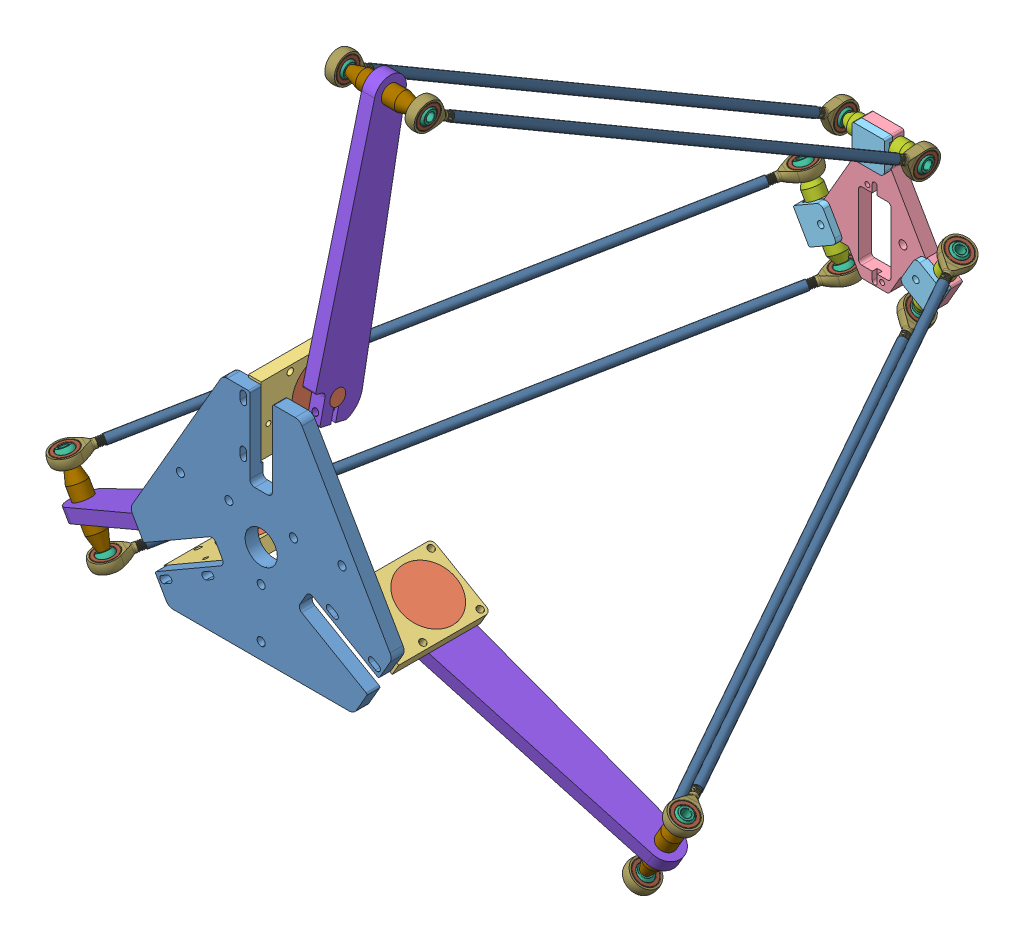
SolidWorks assembly Complete Delta, configuration Default. Lengths in mm.
Overall size (410.24 361.69 424.53).
80 component instances, 12 part files, 73 mates.
Components (placement in the parent):
- BaseA-1: BaseA [Default] at (45.3855 64.0926 134.0736) size (160.83 140.62 8)
- Fake Motor-1: Fake Motor [Default] at (105.2709 46.8266 98.5736) x (0.306794 -0.177128 -0.935149) z (-0.5 -0.866025 0) size (35 35 18.9)
- PartARM-1: PartARM [Default] at (0.4819 20.8459 106.5736) x (0 0 -1) z (-0.5 0.866025 0) size (57 42 8)
- PartARM-3: PartARM [Default] at (30.3764 124.5863 106.5736) x (0 0 -1) z (1 0 0) size (57 42 8)
- PartARM-4: PartARM [Default] at (105.2709 46.8266 106.5736) x (0 0 -1) z (-0.5 -0.866025 0) size (57 42 8)
- Fake Motor-2: Fake Motor [Default] at (30.3764 124.5863 98.5736) x (0 -0.708277 -0.705934) z (1 0 0) size (35 35 18.9)
- Fake Motor-3: Fake Motor [Default] at (0.4819 20.8459 98.5736) x (0.204518 0.118079 -0.971715) z (-0.5 0.866025 0) size (35 35 18.9)
- EndEffector-1: EndEffector [Default] at (49.9985 55.9724 -241.0355) size (92.41 85 8)
- PartKhoaTruc-1: PartKhoaTruc [Default] at (49.9985 93.9724 -234.0355) x (-1 0 0) z (0 0 1) size (20 20 5)
- PartKhoaTruc-2: PartKhoaTruc [Default] at (17.0895 36.9724 -234.0355) x (0.5 -0.866025 0) z (0 0 1) size (20 20 5)
- PartKhoaTruc-3: PartKhoaTruc [Default] at (82.9075 36.9724 -234.0355) x (0.5 0.866025 0) z (0 0 1) size (20 20 5)
- MixShortTruNhua-2: MixShortTruNhua [Default] at (101.7595 61.1502 -247.4039) x (-0.858812 0.495836 -0.128795) z (-0.11154 0.064398 0.991671) size (15.13 19 15.13)
  - Ball Joint 5x008-1: Ball Joint 5x008 [M22*1.5] at (0.7661 5.3646 10.6063) size (11.11 8 11.11)
  - Short Tru Nhua-1: Short Tru Nhua [Default] at (0.7661 20.3646 10.6063) x (-0.852463 0 -0.522787) z (-0.522787 0 0.852463) size (11 11 11)
- MixShortTruNhua-7: MixShortTruNhua [Default] at (80.3631 98.0377 -247.4375) x (0 0.96719 0.254053) z (0 -0.254053 0.96719) size (15.13 19 15.13)
  - Ball Joint 5x008-1: Ball Joint 5x008 [M22*1.5] at (0.7661 5.3646 10.6063) size (11.11 8 11.11)
  - Short Tru Nhua-1: Short Tru Nhua [Default] at (0.7661 20.3646 10.6063) x (-0.852463 0 -0.522787) z (-0.522787 0 0.852463) size (11 11 11)
- Short Tru Nhua-2: Short Tru Nhua [Default] at (20.2608 27.2563 -236.9846) x (-0.838926 -0.484354 -0.248203) z (-0.21495 -0.124102 0.968708) size (11 11 11)
- Ball Joint 5x008-2: Ball Joint 5x008 [M22*1.5] at (27.7608 14.2659 -236.9846) x (0.768045 0.443431 -0.462034) z (0.400133 0.231017 0.886862) size (11.11 8 11.11)
- Short Tru Nhua-4: Short Tru Nhua [Default] at (39.9985 96.0841 -236.9846) x (0 0.948616 0.316428) z (0 -0.316428 0.948616) size (11 11 11)
- Ball Joint 5x008-4: Ball Joint 5x008 [M22*1.5] at (24.9985 96.0841 -236.9846) x (0 -0.650134 0.759819) z (0 0.759819 0.650134) size (11.11 8 11.11)
- Short Tru Nhua-5: Short Tru Nhua [Default] at (10.2608 44.5768 -236.9846) x (0.751736 0.434015 0.496513) z (-0.429993 -0.248256 0.868029) size (11 11 11)
- Ball Joint 5x008-5: Ball Joint 5x008 [M22*1.5] at (2.7608 57.5672 -236.9846) x (-0.416032 -0.240196 -0.877053) z (-0.759551 -0.438527 0.480393) size (11.11 8 11.11)
- Short Tru Nhua-6: Short Tru Nhua [Default] at (79.7363 27.2563 -236.9846) x (-0.333512 0.192553 0.922872) z (0.799231 -0.461436 0.385106) size (11 11 11)
- Ball Joint 5x008-6: Ball Joint 5x008 [M22*1.5] at (72.2363 14.2659 -236.9846) x (0.133521 -0.077088 0.988043) z (-0.855671 0.494022 0.154177) size (11.11 8 11.11)
- MixLongTruNhua-1: MixLongTruNhua [Default] at (204.4836 -62.7208 81.8381) x (-0.585603 0.338098 -0.736721) z (0.638019 -0.368361 -0.676197) size (120.45 58 161.7)
  - CanhTayTren-1: CanhTayTren [Default] at (42.6073 26.3646 -53.4371) x (-0.837169 0 -0.546944) z (0 1 0) size (30.85 173 8)
  - Ball Joint 5x008-1: Ball Joint 5x008 [M22*1.5] at (0.7661 5.3646 10.6063) size (11.11 8 11.11)
  - Long Tru Nhua-1: Long Tru Nhua [Default] at (0.7661 26.3646 10.6063) x (-0.515153 0 -0.857098) z (-0.857098 0 0.515153) size (11 17 11)
  - Long Tru Nhua-2: Long Tru Nhua [Default] at (0.7661 34.3646 10.6063) x (0.837169 0 -0.546944) z (0.546944 0 0.837169) size (11 17 11)
  - Ball Joint 5x008-2: Ball Joint 5x008 [M22*1.5] at (0.7661 55.3646 10.6063) x (-1 0 0) z (0 0 1) size (11.11 8 11.11)
  - Assem2^MixLongTruNhua-1: Assem2^MixLongTruNhua [Default] at origin (virtual)
- MixLongTruNhua-2: MixLongTruNhua [Default] at (-143.5617 -10.0507 78.0616) x (0.602545 0.347879 -0.718275) z (-0.622045 -0.359138 -0.695759) size (120.45 58 161.7)
  - CanhTayTren-1: CanhTayTren [Default] at (42.6073 26.3646 -53.4371) x (-0.837169 0 -0.546944) z (0 1 0) size (30.85 173 8)
  - Ball Joint 5x008-1: Ball Joint 5x008 [M22*1.5] at (0.7661 5.3646 10.6063) size (11.11 8 11.11)
  - Long Tru Nhua-1: Long Tru Nhua [Default] at (0.7661 26.3646 10.6063) x (-0.515153 0 -0.857098) z (-0.857098 0 0.515153) size (11 17 11)
  - Long Tru Nhua-2: Long Tru Nhua [Default] at (0.7661 34.3646 10.6063) x (0.837169 0 -0.546944) z (0.546944 0 0.837169) size (11 17 11)
  - Ball Joint 5x008-2: Ball Joint 5x008 [M22*1.5] at (0.7661 55.3646 10.6063) x (-1 0 0) z (0 0 1) size (11.11 8 11.11)
  - Assem2^MixLongTruNhua-1: Assem2^MixLongTruNhua [Default] at origin (virtual)
- CanhTayTren-1: CanhTayTren [Default] at (49.2764 196.3451 82.6699) x (0 0.216376 0.97631) z (-1 0 0) size (30.85 173 8)
- Long Tru Nhua-1: Long Tru Nhua [Default] at (41.2764 271.0328 66.1172) x (0 0.837169 -0.546944) z (0 0.546944 0.837169) size (11 17 11)
- Ball Joint 5x008-7: Ball Joint 5x008 [M22*1.5] at (70.2764 271.0328 66.1172) x (0 1 0) z (0 0 1) size (11.11 8 11.11)
- Ball Joint 5x008-8: Ball Joint 5x008 [M22*1.5] at (20.2764 271.0328 66.1172) x (0 -1 0) z (0 0 1) size (11.11 8 11.11)
- Long Tru Nhua-2: Long Tru Nhua [Default] at (49.2764 271.0328 66.1172) x (0 -0.515153 -0.857098) z (0 -0.857098 0.515153) size (11 17 11)
- SubTayDuoi-1: SubTayDuoi [Default] at (-102.2129 -22.5698 -236.0534) x (0.781539 -0.423316 -0.458259) z (0.403566 -0.217111 0.888818) size (18 6.77 368)
  - TayDuoi-1: TayDuoi [Default] at (122.3807 165.3749 80.2646) size (5.5 5.5 314)
  - Ball Washer-1: Ball Washer [M5*0.8] at (122.3807 165.3749 62.2646) x (-1 0 0) z (0 0 1) size (14.4 6 14.4)
  - Male Rod End Bearing-1: Male Rod End Bearing [M5*0.8] at (122.3807 165.3749 62.2646) x (0 0 1) z (1 0 0) size (42.16 6.77 18)
  - Ball Washer-2: Ball Washer [M5*0.8] at (122.3807 165.3749 412.2646) size (14.4 6 14.4)
  - Male Rod End Bearing-2: Male Rod End Bearing [M5*0.8] at (122.3807 165.3749 412.2646) x (0 0 -1) z (1 0 0) size (42.16 6.77 18)
- SubTayDuoi-2: SubTayDuoi [Default] at (-22.2485 -145.5265 -371.7741) x (0.883545 0.104191 0.45661) z (-0.427932 -0.216589 0.877476) size (18 6.77 368)
  - TayDuoi-1: TayDuoi [Default] at (122.3807 165.3749 80.2646) size (5.5 5.5 314)
  - Ball Washer-1: Ball Washer [M5*0.8] at (122.3807 165.3749 62.2646) x (-1 0 0) z (0 0 1) size (14.4 6 14.4)
  - Male Rod End Bearing-1: Male Rod End Bearing [M5*0.8] at (122.3807 165.3749 62.2646) x (0 0 1) z (1 0 0) size (42.16 6.77 18)
  - Ball Washer-2: Ball Washer [M5*0.8] at (122.3807 165.3749 412.2646) size (14.4 6 14.4)
  - Male Rod End Bearing-2: Male Rod End Bearing [M5*0.8] at (122.3807 165.3749 412.2646) x (0 0 -1) z (1 0 0) size (42.16 6.77 18)
- SubTayDuoi-3: SubTayDuoi [Default] at (-44.8159 -103.6611 -370.9422) x (0.88073 0.118074 0.458664) z (-0.427932 -0.216589 0.877476) size (18 6.77 368)
  - TayDuoi-1: TayDuoi [Default] at (122.3807 165.3749 80.2646) size (5.5 5.5 314)
  - Ball Washer-1: Ball Washer [M5*0.8] at (122.3807 165.3749 62.2646) x (-1 0 0) z (0 0 1) size (14.4 6 14.4)
  - Male Rod End Bearing-1: Male Rod End Bearing [M5*0.8] at (122.3807 165.3749 62.2646) x (0 0 1) z (1 0 0) size (42.16 6.77 18)
  - Ball Washer-2: Ball Washer [M5*0.8] at (122.3807 165.3749 412.2646) size (14.4 6 14.4)
  - Male Rod End Bearing-2: Male Rod End Bearing [M5*0.8] at (122.3807 165.3749 412.2646) x (0 0 -1) z (1 0 0) size (42.16 6.77 18)
- SubTayDuoi-4: SubTayDuoi [Default] at (-142.5039 166.2342 -351.9831) x (0.024787 -0.86565 0.500035) z (-0.013492 0.499853 0.866005) size (18 6.77 368)
  - TayDuoi-1: TayDuoi [Default] at (122.3807 165.3749 80.2646) size (5.5 5.5 314)
  - Ball Washer-1: Ball Washer [M5*0.8] at (122.3807 165.3749 62.2646) x (-1 0 0) z (0 0 1) size (14.4 6 14.4)
  - Male Rod End Bearing-1: Male Rod End Bearing [M5*0.8] at (122.3807 165.3749 62.2646) x (0 0 1) z (1 0 0) size (42.16 6.77 18)
  - Ball Washer-2: Ball Washer [M5*0.8] at (122.3807 165.3749 412.2646) size (14.4 6 14.4)
  - Male Rod End Bearing-2: Male Rod End Bearing [M5*0.8] at (122.3807 165.3749 412.2646) x (0 0 -1) z (1 0 0) size (42.16 6.77 18)
- SubTayDuoi-5: SubTayDuoi [Default] at (-77.8176 182.3956 -361.0826) x (-0.090132 -0.863166 0.496811) z (-0.013492 0.499853 0.866005) size (18 6.77 368)
  - TayDuoi-1: TayDuoi [Default] at (122.3807 165.3749 80.2646) size (5.5 5.5 314)
  - Ball Washer-1: Ball Washer [M5*0.8] at (122.3807 165.3749 62.2646) x (-1 0 0) z (0 0 1) size (14.4 6 14.4)
  - Male Rod End Bearing-1: Male Rod End Bearing [M5*0.8] at (122.3807 165.3749 62.2646) x (0 0 1) z (1 0 0) size (42.16 6.77 18)
  - Ball Washer-2: Ball Washer [M5*0.8] at (122.3807 165.3749 412.2646) size (14.4 6 14.4)
  - Male Rod End Bearing-2: Male Rod End Bearing [M5*0.8] at (122.3807 165.3749 412.2646) x (0 0 -1) z (1 0 0) size (42.16 6.77 18)
- SubTayDuoi-6: SubTayDuoi [Default] at (-137.2814 -31.705 -223.1361) x (0.681042 -0.577437 -0.450276) z (0.403566 -0.217111 0.888818) size (18 6.77 368)
  - TayDuoi-1: TayDuoi [Default] at (122.3807 165.3749 80.2646) size (5.5 5.5 314)
  - Ball Washer-1: Ball Washer [M5*0.8] at (122.3807 165.3749 62.2646) x (-1 0 0) z (0 0 1) size (14.4 6 14.4)
  - Male Rod End Bearing-1: Male Rod End Bearing [M5*0.8] at (122.3807 165.3749 62.2646) x (0 0 1) z (1 0 0) size (42.16 6.77 18)
  - Ball Washer-2: Ball Washer [M5*0.8] at (122.3807 165.3749 412.2646) size (14.4 6 14.4)
  - Male Rod End Bearing-2: Male Rod End Bearing [M5*0.8] at (122.3807 165.3749 412.2646) x (0 0 -1) z (1 0 0) size (42.16 6.77 18)
Mates (geometry in assembly coordinates):
- Concentric3: concentric aligned: circle of BaseA-1; circle of PartARM-3
- Parallel2: parallel aligned: line of BaseA-1 through (38.3764 143.0926 135.0736) axis (0 -1 0); line of PartARM-3 through (38.3764 145.5863 135.0736) axis (0 -1 0)
- Coincident7: coincident anti-aligned: plane of BaseA-1 through (30.3764 104.3426 135.0736) normal (0 0 -1); plane of PartARM-3 through (38.3764 103.5863 135.0736) normal (0 0 1)
- Coincident8: coincident anti-aligned: plane of BaseA-1 through (18.0285 30.9764 135.0736) normal (0 0 -1); plane of PartARM-1 through (14.6684 38.2741 135.0736) normal (0 0 1)
- Coincident9: coincident aligned: circle of BaseA-1; circle of PartARM-1
- Coincident10: coincident aligned: line of BaseA-1 through (-19.53 18.5296 135.0736) axis (0.866025 0.5 0); line of PartARM-1 through (-21.7047 17.2741 135.0736) axis (0.866025 0.5 0)
- Coincident11: coincident anti-aligned: plane of BaseA-1 through (87.738 56.9493 135.0736) normal (0 0 -1); plane of PartARM-4 through (83.0844 50.3984 135.0736) normal (0 0 1)
- Coincident12: coincident aligned: circle of BaseA-1; circle of PartARM-4
- Coincident13: coincident aligned: line of BaseA-1 through (117.2965 30.6461 135.0736) axis (-0.866025 0.5 0); line of PartARM-4 through (119.4575 29.3984 135.0736) axis (-0.866025 0.5 0)
- Coincident14: coincident aligned: plane of PartARM-3 through (38.3764 124.5863 106.5736) normal (1 0 0); plane of Fake Motor-2 through (38.3764 124.5863 98.5736) normal (1 0 0)
- Coincident15: coincident aligned: circle of PartARM-3; circle of Fake Motor-2
- Coincident16: coincident aligned: plane of Fake Motor-1 through (101.2709 39.8984 98.5736) normal (-0.5 -0.866025 0); plane of PartARM-4 through (101.2709 39.8984 106.5736) normal (-0.5 -0.866025 0)
- Coincident17: coincident aligned: circle of Fake Motor-1; circle of PartARM-4
- Coincident18: coincident aligned: plane of PartARM-1 through (-3.5181 27.7741 106.5736) normal (-0.5 0.866025 0); plane of Fake Motor-3 through (-3.5181 27.7741 98.5736) normal (-0.5 0.866025 0)
- Coincident19: coincident aligned: circle of PartARM-1; circle of Fake Motor-3
- Concentric14: concentric aligned: cylinder of EndEffector-1 through (49.9985 89.9724 -241.0355) axis (0 0 1) radius 1.5; cylinder of PartKhoaTruc-1 through (49.9985 89.9724 -234.0355) axis (0 0 1) radius 2
- Coincident31: coincident anti-aligned: line of EndEffector-1 through (40.9985 103.9724 -234.0355) axis (1 0 0); line of PartKhoaTruc-1 through (58.9985 103.9724 -234.0355) axis (-1 0 0)
- Concentric15: concentric aligned: cylinder of EndEffector-1 through (20.5536 38.9724 -241.0355) axis (0 0 1) radius 1.5; cylinder of PartKhoaTruc-2 through (20.5536 38.9724 -234.0355) axis (0 0 1) radius 2
- Coincident32: coincident anti-aligned: line of EndEffector-1 through (12.9293 24.1781 -234.0355) axis (-0.5 0.866025 0); line of PartKhoaTruc-2 through (3.9293 39.7666 -234.0355) axis (0.5 -0.866025 0)
- Concentric16: concentric aligned: cylinder of EndEffector-1 through (79.4434 38.9724 -241.0355) axis (0 0 1) radius 1.5; cylinder of PartKhoaTruc-3 through (79.4434 38.9724 -234.0355) axis (0 0 1) radius 2
- Coincident33: coincident aligned: line of EndEffector-1 through (87.0677 24.1781 -234.0355) axis (0.5 0.866025 0); line of PartKhoaTruc-3 through (87.0677 24.1781 -234.0355) axis (0.5 0.866025 0)
- Concentric34: concentric anti-aligned: circle of Short Tru Nhua-2; circle of Ball Joint 5x008-2
- Coincident102: coincident anti-aligned: plane of Short Tru Nhua-2 through (23.244 16.2769 -237.7292) normal (0.5 -0.866025 0); plane of Ball Joint 5x008-2 through (28.7213 19.4393 -238.7655) normal (-0.5 0.866025 0)
- Concentric36: concentric anti-aligned: circle of Short Tru Nhua-4; circle of Ball Joint 5x008-4
- Coincident104: coincident anti-aligned: plane of Short Tru Nhua-4 through (28.9985 98.9299 -236.0353) normal (-1 0 0); plane of Ball Joint 5x008-4 through (28.9985 93.578 -234.0557) normal (1 0 0)
- Concentric37: concentric anti-aligned: circle of Short Tru Nhua-5; circle of Ball Joint 5x008-5
- Coincident105: coincident anti-aligned: plane of Short Tru Nhua-5 through (7.016 55.4051 -235.495) normal (-0.5 0.866025 0); plane of Ball Joint 5x008-5 through (3.1571 53.1772 -240.3653) normal (0.5 -0.866025 0)
- Concentric38: concentric anti-aligned: circle of Short Tru Nhua-6; circle of Ball Joint 5x008-6
- Coincident106: coincident anti-aligned: plane of Short Tru Nhua-6 through (73.2357 18.3077 -234.2159) normal (-0.5 -0.866025 0); plane of Ball Joint 5x008-6 through (74.7509 17.4329 -233.176) normal (0.5 0.866025 0)
- Coincident107: coincident: point of EndEffector-1; circle of Short Tru Nhua-6
- Coincident108: coincident: point of PartKhoaTruc-3; circle of Short Tru Nhua-6
- Coincident109: coincident anti-aligned: plane of PartKhoaTruc-3 through (86.5677 23.3121 -229.0355) normal (-0.5 -0.866025 0); plane of Short Tru Nhua-6 through (78.0687 28.219 -232.3702) normal (0.5 0.866025 0)
- Coincident120: coincident: point of EndEffector-1; circle of MixShortTruNhua-2/Short Tru Nhua-1
- Coincident121: coincident: point of PartKhoaTruc-3; circle of MixShortTruNhua-2/Short Tru Nhua-1
- Coincident122: coincident anti-aligned: plane of EndEffector-1 through (81.5677 49.2929 -233.0355) normal (0.5 0.866025 0); plane of MixShortTruNhua-2/Short Tru Nhua-1 through (93.6883 42.295 -239.0278) normal (-0.5 -0.866025 0)
- Concentric39: concentric anti-aligned: circle of Fake Motor-1; circle of MixLongTruNhua-1/CanhTayTren-1
- Coincident124: coincident aligned: plane of Fake Motor-1 through (95.8209 30.4588 98.5736) normal (-0.5 -0.866025 0); plane of MixLongTruNhua-1/CanhTayTren-1 through (158.621 -5.7989 86.5824) normal (-0.5 -0.866025 0)
- Coincident137: coincident: point of PartKhoaTruc-1; circle of MixShortTruNhua-7/Short Tru Nhua-1
- Coincident138: coincident: point of EndEffector-1; circle of MixShortTruNhua-7/Short Tru Nhua-1
- Coincident139: coincident anti-aligned: plane of PartKhoaTruc-1 through (59.9985 103.9724 -229.0355) normal (1 0 0); plane of MixShortTruNhua-7/Short Tru Nhua-1 through (59.9985 92.6257 -240.5956) normal (-1 0 0)
- Coincident140: coincident: point of PartKhoaTruc-2; circle of Short Tru Nhua-5
- Coincident141: coincident: point of EndEffector-1; circle of Short Tru Nhua-5
- Coincident142: coincident anti-aligned: plane of EndEffector-1 through (18.4293 49.2929 -233.0355) normal (-0.5 0.866025 0); plane of Short Tru Nhua-5 through (14.0194 46.7469 -234.502) normal (0.5 -0.866025 0)
- Coincident143: coincident: point of PartKhoaTruc-1; circle of Short Tru Nhua-4
- Coincident144: coincident: point of EndEffector-1; circle of Short Tru Nhua-4
- Coincident145: coincident anti-aligned: plane of EndEffector-1 through (39.9985 86.6519 -233.0355) normal (-1 0 0); plane of Short Tru Nhua-4 through (39.9985 100.8271 -235.4024) normal (1 0 0)
- Coincident149: coincident: point of EndEffector-1; circle of Short Tru Nhua-2
- Coincident150: coincident: point of PartKhoaTruc-2; circle of Short Tru Nhua-2
- Coincident151: coincident anti-aligned: plane of PartKhoaTruc-2 through (13.4293 23.3121 -229.0355) normal (0.5 -0.866025 0); plane of Short Tru Nhua-2 through (16.0661 24.8345 -238.2256) normal (-0.5 0.866025 0)
- Concentric44: concentric aligned: circle of CanhTayTren-1; circle of Long Tru Nhua-2
- Concentric45: concentric anti-aligned: circle of CanhTayTren-1; circle of Long Tru Nhua-1
- Concentric46: concentric anti-aligned: circle of Ball Joint 5x008-7; circle of Long Tru Nhua-2
- Concentric47: concentric anti-aligned: circle of Long Tru Nhua-1; circle of Ball Joint 5x008-8
- Coincident152: coincident anti-aligned: plane of Ball Joint 5x008-7 through (66.2764 274.8874 66.1172) normal (-1 0 0); plane of Long Tru Nhua-2 through (66.2764 269.4873 63.5459) normal (1 0 0)
- Coincident153: coincident anti-aligned: plane of CanhTayTren-1 through (41.2764 196.3451 82.6699) normal (-1 0 0); plane of Long Tru Nhua-1 through (41.2764 275.2186 63.3824) normal (1 0 0)
- Coincident154: coincident anti-aligned: plane of CanhTayTren-1 through (49.2764 196.3451 82.6699) normal (1 0 0); plane of Long Tru Nhua-2 through (49.2764 268.457 61.8317) normal (-1 0 0)
- Coincident155: coincident anti-aligned: plane of Long Tru Nhua-1 through (24.2764 273.5443 64.4763) normal (-1 0 0); plane of Ball Joint 5x008-8 through (24.2764 267.1782 66.1172) normal (1 0 0)
- Concentric48: concentric anti-aligned: circle of Fake Motor-2; circle of CanhTayTren-1
- Coincident157: coincident aligned: plane of Fake Motor-2 through (49.2764 124.5863 98.5736) normal (1 0 0); plane of CanhTayTren-1 through (49.2764 196.3451 82.6699) normal (1 0 0)
- Concentric50: concentric anti-aligned: circle of Fake Motor-3; circle of MixLongTruNhua-2/CanhTayTren-1
- Coincident163: coincident aligned: plane of Fake Motor-3 through (-8.9681 37.2138 98.5736) normal (-0.5 0.866025 0); plane of MixLongTruNhua-2/CanhTayTren-1 through (-71.4663 1.1304 84.6372) normal (-0.5 0.866025 0)
- Concentric51: concentric: sphere of MixLongTruNhua-1/Ball Joint 5x008-2; unknown of SubTayDuoi-1/Ball Washer-2
- Concentric52: concentric: unknown of MixShortTruNhua-2/Ball Joint 5x008-1; unknown of SubTayDuoi-1/Ball Washer-1
- Concentric53: concentric: unknown of MixLongTruNhua-1/Ball Joint 5x008-1; unknown of SubTayDuoi-6/Ball Washer-2
- Concentric54: concentric: unknown of Ball Joint 5x008-6; unknown of SubTayDuoi-6/Ball Washer-1
- Concentric55: concentric: unknown of MixLongTruNhua-2/Ball Joint 5x008-2; unknown of SubTayDuoi-2/Ball Washer-2
- Concentric56: concentric: unknown of Ball Joint 5x008-2; unknown of SubTayDuoi-2/Ball Washer-1
- Concentric57: concentric: unknown of MixLongTruNhua-2/Ball Joint 5x008-1; unknown of SubTayDuoi-3/Ball Washer-2
- Concentric58: concentric: unknown of Ball Joint 5x008-5; unknown of SubTayDuoi-3/Ball Washer-1
- Concentric59: concentric: unknown of Ball Joint 5x008-8; unknown of SubTayDuoi-4/Ball Washer-2
- Concentric60: concentric: unknown of Ball Joint 5x008-4; unknown of SubTayDuoi-4/Ball Washer-1
- Concentric61: concentric: unknown of Ball Joint 5x008-7; unknown of SubTayDuoi-5/Ball Washer-2
- Concentric62: concentric: unknown of MixShortTruNhua-7/Ball Joint 5x008-1; unknown of SubTayDuoi-5/Ball Washer-1
